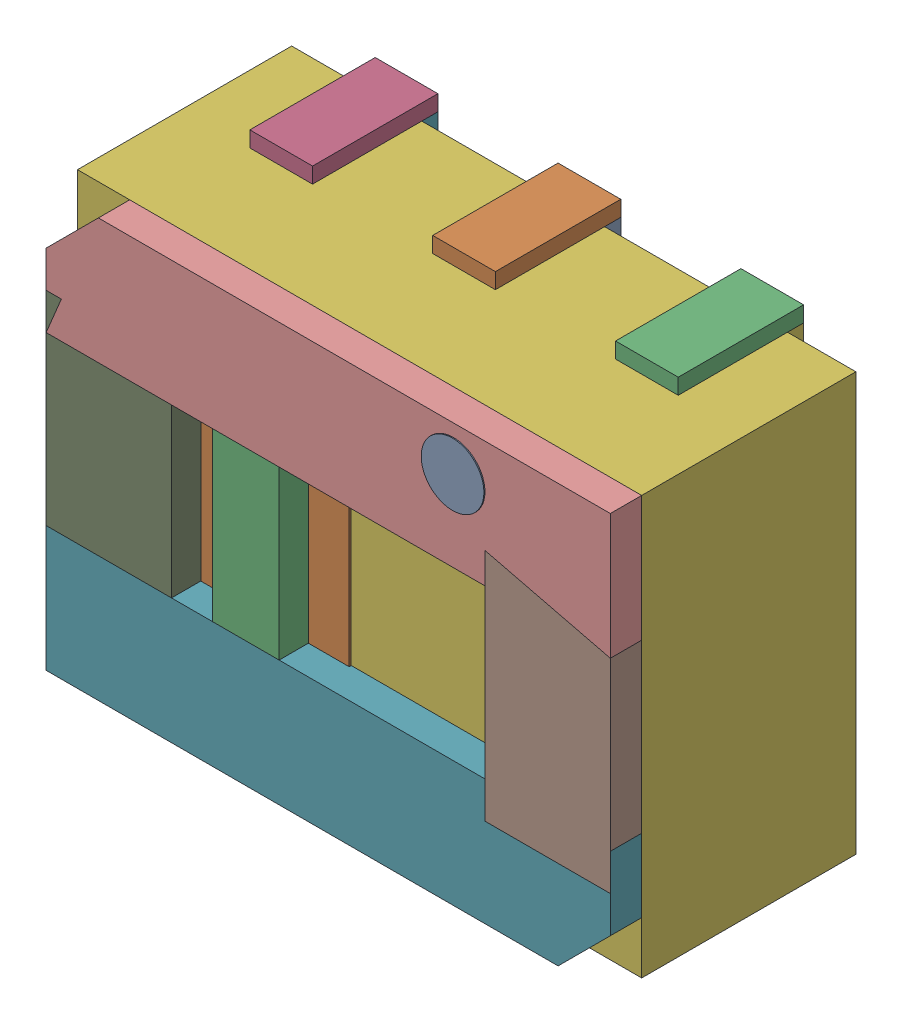
SolidWorks assembly SW10.step, configuration Default. Lengths in mm.
Overall size (5.4 4.31 2.51).
40 component instances, 10 part files, 0 mates.
Components (placement in the parent):
- 6401095888.step-1: 6401095888.step [Default] at (21.8246 -26.1061 2.5) x (-1 0 0) z (0 0 1) size (0.6 0.6 0.01)
  - Cylinder (6).step-1: Cylinder (6).step [Default] at origin size (0.6 0.6 0.01)
- 6401095728.step-1: 6401095728.step [Default] at (19.8347 -27.686 2.2) size (1.42 1.6 0.02)
  - Extruded (16).step-1: Extruded (16).step [Default] at origin size (1.42 1.6 0.02)
- 6401095488.step-1: 6401095488.step [Default] at (19.8347 -27.686 2.22) size (0.64 1.6 0.28)
  - Extruded (17).step-1: Extruded (17).step [Default] at origin size (0.64 1.6 0.28)
- 6401095248.step-1: 6401095248.step [Default] at (18.8749 -29.3408 0) size (0.6 0.7 0.15)
  - Extruded (18).step-1: Extruded (18).step [Default] at origin size (0.6 0.7 0.15)
- 6401095008.step-1: 6401095008.step [Default] at (18.8749 -29.7659 0) size (0.6 0.15 1.2)
  - Extruded (19).step-1: Extruded (19).step [Default] at origin size (0.6 0.15 1.2)
- 6440853216.step-1: 6440853216.step [Default] at (20.6247 -27.6861 0.15) size (5.4 4 2.05)
  - Extruded (20).step-1: Extruded (20).step [Default] at origin size (5.4 4 2.05)
- 6440852976.step-1: 6440852976.step [Default] at (20.6247 -29.086 2.2) size (5.4 1.2 0.3)
  - Extruded (21).step-1: Extruded (21).step [Default] at origin size (5.4 1.2 0.3)
- 6440852736.step-1: 6440852736.step [Default] at (22.7247 -27.6861 2.2) size (1.2 2.3 0.3)
  - Extruded (22).step-1: Extruded (22).step [Default] at origin size (1.2 2.3 0.3)
- 6440852496.step-1: 6440852496.step [Default] at (18.5247 -27.6861 2.2) size (1.2 2.3 0.3)
  - Extruded (23).step-1: Extruded (23).step [Default] at origin size (1.2 2.3 0.3)
- 6440851296.step-1: 6440851296.step [Default] at (20.6247 -26.286 2.2) size (5.4 1.2 0.3)
  - Extruded (24).step-1: Extruded (24).step [Default] at origin size (5.4 1.2 0.3)
- 6401095248.step-2: 6401095248.step [Default] at (22.3749 -29.3408 0) size (0.6 0.7 0.15)
  - Extruded (18).step-1: Extruded (18).step [Default] at origin size (0.6 0.7 0.15)
- 6401095008.step-2: 6401095008.step [Default] at (22.3749 -29.7659 0) size (0.6 0.15 1.2)
  - Extruded (19).step-1: Extruded (19).step [Default] at origin size (0.6 0.15 1.2)
- 6401095248.step-3: 6401095248.step [Default] at (20.6245 -26.0313 0) size (0.6 0.7 0.15)
  - Extruded (18).step-1: Extruded (18).step [Default] at origin size (0.6 0.7 0.15)
- 6401095008.step-3: 6401095008.step [Default] at (20.6245 -25.6063 0) size (0.6 0.15 1.2)
  - Extruded (19).step-1: Extruded (19).step [Default] at origin size (0.6 0.15 1.2)
- 6401095008.step-4: 6401095008.step [Default] at (22.3745 -25.6063 0) size (0.6 0.15 1.2)
  - Extruded (19).step-1: Extruded (19).step [Default] at origin size (0.6 0.15 1.2)
- 6401095008.step-5: 6401095008.step [Default] at (18.8745 -25.6063 0) size (0.6 0.15 1.2)
  - Extruded (19).step-1: Extruded (19).step [Default] at origin size (0.6 0.15 1.2)
- 6401095008.step-6: 6401095008.step [Default] at (20.6247 -29.7661 0) size (0.6 0.15 1.2)
  - Extruded (19).step-1: Extruded (19).step [Default] at origin size (0.6 0.15 1.2)
- 6401095248.step-4: 6401095248.step [Default] at (22.3745 -26.0313 0) size (0.6 0.7 0.15)
  - Extruded (18).step-1: Extruded (18).step [Default] at origin size (0.6 0.7 0.15)
- 6401095248.step-5: 6401095248.step [Default] at (18.8745 -26.0313 0) size (0.6 0.7 0.15)
  - Extruded (18).step-1: Extruded (18).step [Default] at origin size (0.6 0.7 0.15)
- 6401095248.step-6: 6401095248.step [Default] at (20.6247 -29.341 0) size (0.6 0.7 0.15)
  - Extruded (18).step-1: Extruded (18).step [Default] at origin size (0.6 0.7 0.15)
